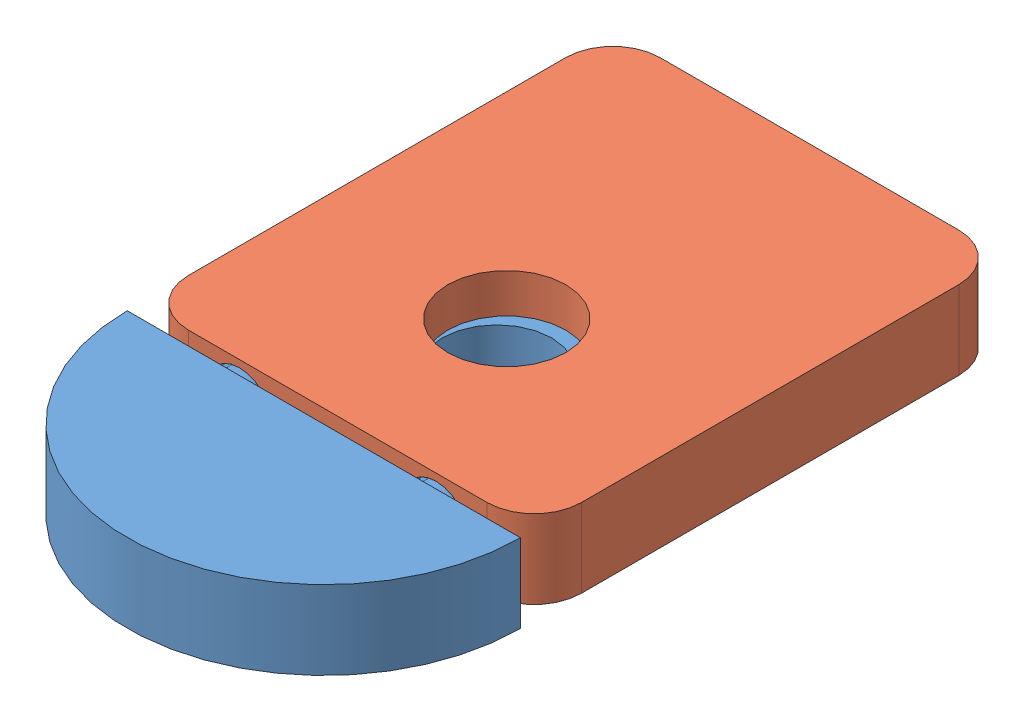
SolidWorks assembly SoapAssembly, configuration Default. Lengths in mm.
Overall size (63.5 12.7 110.18).
2 component instances, 2 part files, 2 mates.
Components (placement in the parent):
- Insertion.Piece-1: Insertion.Piece [Default] at (-0.8855 51.6108 96.3371) size (63.5 12.7 107.95)
- TopEnd-1: TopEnd [Default] at (-0.8855 51.6108 17.9046) x (1 0 0) z (0 -1 0) size (63.5 76.2 12.7)
Mates (geometry in assembly coordinates):
- Concentric1: concentric aligned: cylinder of Insertion.Piece-1 through (46.7395 57.9608 34.1071) axis (0 0 1) radius 5.08; cylinder of TopEnd-1 through (46.7395 57.9608 24.2546) axis (0 0 1) radius 5.207
- Coincident2: coincident anti-aligned: plane of Insertion.Piece-1 through (40.6181 57.9608 20.1371) normal (0 1 0); plane of TopEnd-1 through (21.2557 57.9608 17.9046) normal (0 -1 0)
